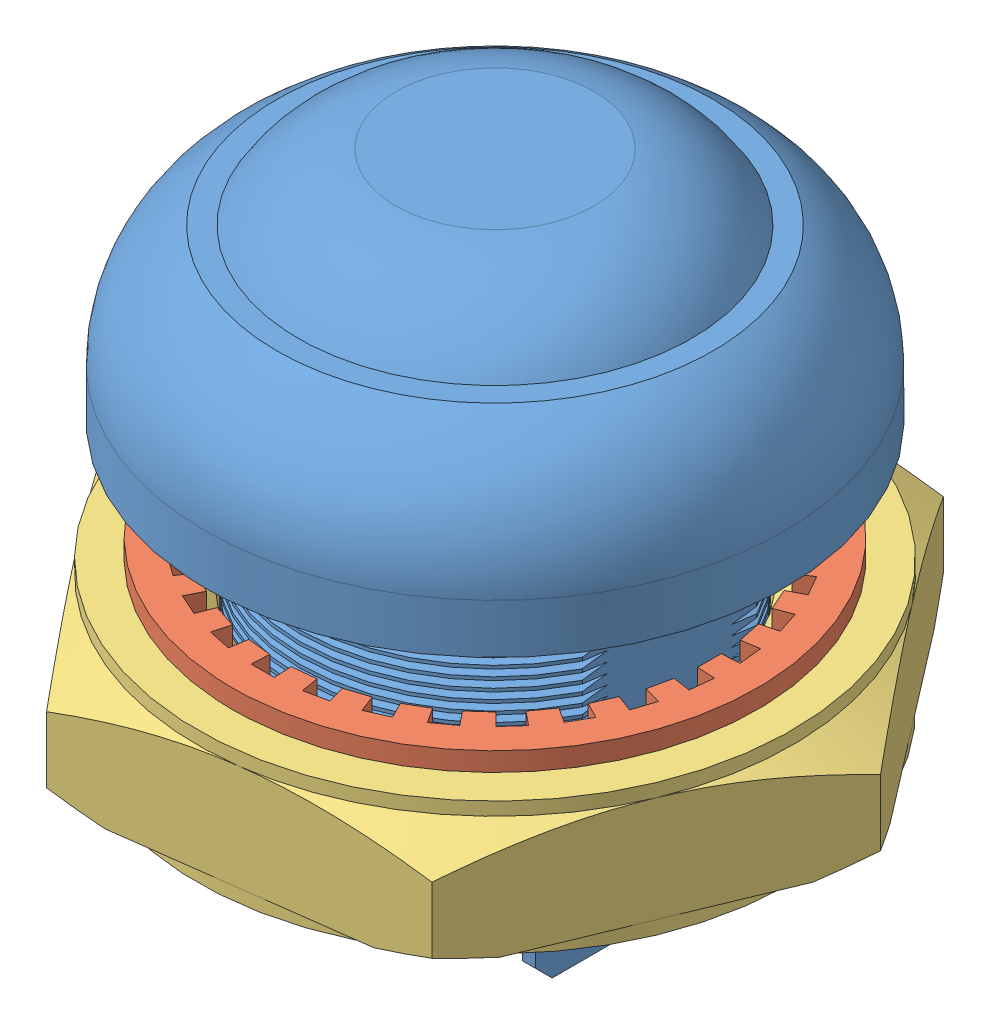
SolidWorks assembly Push Botton, configuration Default. Lengths in mm.
Overall size (22.97 19.97 20.57).
3 component instances, 3 part files, 3 mates.
Components (placement in the parent):
- Push Botton_Button-1: Push Botton_Button [Default] at (-68.6485 15.5776 27.5677) size (17.5 19.97 17.5)
- Push Botton_Internal spur gear-1: Push Botton_Internal spur gear [Default] at (-68.6485 11.9914 27.5677) size (15.88 0.57 15.88)
- Push Botton_Hex nut-1: Push Botton_Hex nut [Default] at (-68.6485 11.9914 27.5677) x (-0.131364 0 -0.991334) z (0 1 0) size (18 20.78 4)
Mates (geometry in assembly coordinates):
- Coincident1: coincident anti-aligned: plane of Push Botton_Internal spur gear-1 through (-68.6485 11.9914 27.5677) normal (0 -1 0); plane of Push Botton_Hex nut-1 through (-66.284 11.9914 45.4117) normal (0 1 0)
- Concentric1: concentric anti-aligned: circle of Push Botton_Internal spur gear-1; circle of Push Botton_Hex nut-1
- Concentric2: concentric aligned: circle of Push Botton_Button-1; cylinder of Push Botton_Hex nut-1 through (-68.6485 1.9914 27.5677) axis (0 1 0) radius 6
